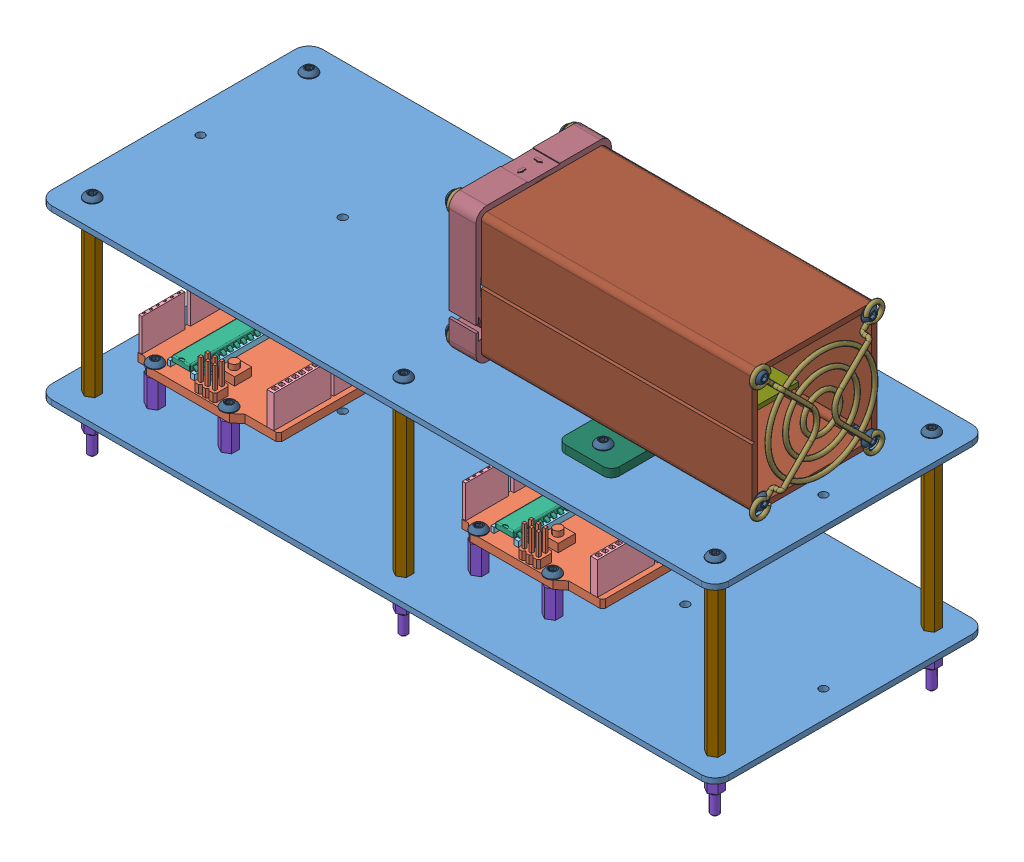
SolidWorks assembly control unit all, configuration Default. Lengths in mm.
Overall size (250 135.43 100).
72 component instances, 16 part files, 86 mates.
Components (placement in the parent):
- control unit enclosure buttom-1: control unit enclosure buttom [Default] at origin size (250 2 100)
- Arduino Uno-1: Arduino Uno [Predeterminado] at (82.475 -17.4682 -25.4621) x (0 0 1) z (-1 0 0) size (76.16 15 51.98)
  - Arduino Board-1: Arduino Board [Predeterminado] at (-14.2075 29.4682 76.4447) size (67.88 14 51.98)
  - Jam Socket-1: Jam Socket [Predeterminado] at origin size (12.01 7 9.62)
  - Pins Socket-1: Pins Socket [Predeterminado] at origin size (43.28 12 50.07)
  - Socket IC-1: Socket IC [Predeterminado] at origin size (35.47 2 10.08)
  - IC-1: IC [Predeterminado] at (0 34.4682 0) x (1 0 0) z (0 1 0) size (35.12 9.79 3)
  - Port USB-1: Port USB [Predeterminado] at (-14.2075 31.4682 76.4447) x (1 0 0) z (0 1 0) size (17.2 12.69 11)
- Arduino Uno-2: Arduino Uno [Predeterminado] at (-30.5497 -17.4682 -18.9941) x (0 0 1) z (-1 0 0) size (76.16 15 51.98)
  - Arduino Board-1: Arduino Board [Predeterminado] at (-14.2075 29.4682 76.4447) size (67.88 14 51.98)
  - Jam Socket-1: Jam Socket [Predeterminado] at origin size (12.01 7 9.62)
  - Pins Socket-1: Pins Socket [Predeterminado] at origin size (43.28 12 50.07)
  - Socket IC-1: Socket IC [Predeterminado] at origin size (35.47 2 10.08)
  - IC-1: IC [Predeterminado] at (0 34.4682 0) x (1 0 0) z (0 1 0) size (35.12 9.79 3)
  - Port USB-1: Port USB [Predeterminado] at (-14.2075 31.4682 76.4447) x (1 0 0) z (0 1 0) size (17.2 12.69 11)
- control unit enclosure buttom-2: control unit enclosure buttom [Default] at (0 62 0) size (250 2 100)
- Threaded spacer,mild steel,M3x10mm,MF-1: Threaded spacer,mild steel,M3x10mm,MF [Default] at (-115.0439 0 40.018) x (1 0 0) z (0 -1 0) size (5 5.77 18)
- Threaded spacer,mild steel,M3x10mm,MF-2: Threaded spacer,mild steel,M3x10mm,MF [Default] at (-0.0439 0 40.018) x (1 0 0) z (0 -1 0) size (5 5.77 18)
- Threaded spacer,mild steel,M3x10mm,MF-3: Threaded spacer,mild steel,M3x10mm,MF [Default] at (-0.0439 0 0.018) x (1 0 0) z (0 -1 0) size (5 5.77 18)
- Threaded spacer,mild steel,M3x10mm,MF-4: Threaded spacer,mild steel,M3x10mm,MF [Default] at (114.9561 0 40.018) x (1 0 0) z (0 -1 0) size (5 5.77 18)
- Threaded spacer,mild steel,M3x10mm,MF-5: Threaded spacer,mild steel,M3x10mm,MF [Default] at (114.9561 0 -39.982) x (1 0 0) z (0 -1 0) size (5 5.77 18)
- Threaded spacer,mild steel,M3x10mm,MF-6: Threaded spacer,mild steel,M3x10mm,MF [Default] at (-0.0439 0 -39.982) x (1 0 0) z (0 -1 0) size (5 5.77 18)
- Threaded spacer,mild steel,M3x10mm,MF-7: Threaded spacer,mild steel,M3x10mm,MF [Default] at (-115.0439 0 -39.982) x (1 0 0) z (0 -1 0) size (5 5.77 18)
- Threaded spacer,mild steel,M3x10mm,MF-8: Threaded spacer,mild steel,M3x10mm,MF [Default] at (8.6552 12 -25.8057) x (1 0 0) z (0 -1 0) size (5 5.77 18)
- Threaded spacer,mild steel,M3x10mm,MF-9: Threaded spacer,mild steel,M3x10mm,MF [Default] at (56.3988 12 -24.9534) x (1 0 0) z (0 -1 0) size (5 5.77 18)
- Threaded spacer,mild steel,M3x10mm,MF-10: Threaded spacer,mild steel,M3x10mm,MF [Default] at (41.1542 12 26.2142) x (1 0 0) z (0 -1 0) size (5 5.77 18)
- Threaded spacer,mild steel,M3x10mm,MF-11: Threaded spacer,mild steel,M3x10mm,MF [Default] at (13.5549 12 25.926) x (1 0 0) z (0 -1 0) size (5 5.77 18)
- Threaded spacer,mild steel,M3x10mm,MF-12: Threaded spacer,mild steel,M3x10mm,MF [Default] at (-56.6259 12 -18.4855) x (1 0 0) z (0 -1 0) size (5 5.77 18)
- Threaded spacer,mild steel,M3x10mm,MF-13: Threaded spacer,mild steel,M3x10mm,MF [Default] at (-71.8705 12 32.6822) x (1 0 0) z (0 -1 0) size (5 5.77 18)
- Threaded spacer,mild steel,M3x10mm,MF-14: Threaded spacer,mild steel,M3x10mm,MF [Default] at (-104.3696 12 -19.3378) x (1 0 0) z (0 -1 0) size (5 5.77 18)
- Threaded spacer,mild steel,M3x10mm,MF-15: Threaded spacer,mild steel,M3x10mm,MF [Default] at (-99.4698 12 32.394) x (1 0 0) z (0 -1 0) size (5 5.77 18)
- M3 60 Hex-1: M3 60 Hex [Default] at (-115.0439 62 -39.982) x (1 0 0) z (0 -1 0) size (5 5.77 60)
- M3 60 Hex-2: M3 60 Hex [Default] at (-0.0439 62 -39.982) x (1 0 0) z (0 -1 0) size (5 5.77 60)
- M3 60 Hex-3: M3 60 Hex [Default] at (114.9561 62 -39.982) x (1 0 0) z (0 -1 0) size (5 5.77 60)
- M3 60 Hex-4: M3 60 Hex [Default] at (114.9561 62 40.018) x (1 0 0) z (0 -1 0) size (5 5.77 60)
- M3 60 Hex-5: M3 60 Hex [Default] at (-0.0439 62 40.018) x (1 0 0) z (0 -1 0) size (5 5.77 60)
- M3 60 Hex-6: M3 60 Hex [Default] at (-115.0439 62 40.018) x (1 0 0) z (0 -1 0) size (5 5.77 60)
- Button Head Socket Cap Screw M3-3: Button Head Socket Cap Screw M3 [M3 x 6] at (56.4427 9 -24.9715) x (0 -1 0) z (0 0 1) size (7.72 5.7 5.7)
- Button Head Socket Cap Screw M3-4: Button Head Socket Cap Screw M3 [M3 x 6] at (41.1981 9 26.1962) x (0 -1 0) z (0 0 1) size (7.72 5.7 5.7)
- Button Head Socket Cap Screw M3-5: Button Head Socket Cap Screw M3 [M3 x 6] at (13.5988 9 25.908) x (0 -1 0) z (0 0 1) size (7.72 5.7 5.7)
- Button Head Socket Cap Screw M3-6: Button Head Socket Cap Screw M3 [M3 x 6] at (8.6991 9 -25.8238) x (0 -1 0) z (0 0 1) size (7.72 5.7 5.7)
- Button Head Socket Cap Screw M3-7: Button Head Socket Cap Screw M3 [M3 x 6] at (-99.4259 9 32.376) x (0 -1 0) z (0 0 1) size (7.72 5.7 5.7)
- Button Head Socket Cap Screw M3-8: Button Head Socket Cap Screw M3 [M3 x 6] at (-71.8267 9 32.6642) x (0 -1 0) z (0 0 1) size (7.72 5.7 5.7)
- Button Head Socket Cap Screw M3-9: Button Head Socket Cap Screw M3 [M3 x 6] at (-56.582 9 -18.5035) x (0 -1 0) z (0 0 1) size (7.72 5.7 5.7)
- Button Head Socket Cap Screw M3-10: Button Head Socket Cap Screw M3 [M3 x 6] at (-104.3257 9 -19.3558) x (0 -1 0) z (0 0 1) size (7.72 5.7 5.7)
- laser driver all-1: laser driver all [Default] at (137.2946 173.2943 62.6746) x (0 0 -1) z (-1 0 0) size (70 56.43 120.4)
  - laser driver box main body-1: laser driver box main body [Default] at (63.0779 83.2943 26.0047) x (1 0 0) z (0 -1 0) size (46 100 46)
  - 50mm fan grill-1: 50mm fan grill [Default] at (63.0022 83.1988 136.0042) x (1 0 0) z (0 -1 0) size (49.4 5.46 49.4)
  - Button Head Socket Cap Screw M3-1: Button Head Socket Cap Screw M3 [M3 x 12] at (84.0779 62.2943 126.0047) x (0 0 -1) z (1 0 0) size (13.72 5.7 5.7)
  - Button Head Socket Cap Screw M3-2: Button Head Socket Cap Screw M3 [M3 x 12] at (42.0779 62.2943 126.0047) x (0 0 -1) z (1 0 0) size (13.72 5.7 5.7)
  - Button Head Socket Cap Screw M3-3: Button Head Socket Cap Screw M3 [M3 x 12] at (42.0779 104.2943 126.0047) x (0 0 -1) z (1 0 0) size (13.72 5.7 5.7)
  - Button Head Socket Cap Screw M3-4: Button Head Socket Cap Screw M3 [M3 x 12] at (84.0779 104.2943 126.0047) x (0 0 -1) z (1 0 0) size (13.72 5.7 5.7)
  - fan_asm-2: fan_asm [Default] at (-332.7982 222.9958 136.0047) x (1 0 0) z (0 1 0) size (54.48 10.28 54.48)
    - fan_case-1: fan_case [Default] at origin size (50 10.1 50)
    - fan-1: fan [Default] at (415.4421 3.5826 -113.9746) x (0.605351 0 0.795959) z (0.795959 0 -0.605351) size (45.4 7.28 44.65)
  - laser driver box mouinting-1: laser driver box mouinting [Default] at (63.0779 106.2943 76.0047) size (70 3 20)
  - Threaded spacer,mild steel,M3x10mm,MF-1: Threaded spacer,mild steel,M3x10mm,MF [Default] at (55.0779 94.2943 76.0047) x (0.924886 0 -0.380244) z (0 1 0) size (5 5.77 18)
  - Threaded spacer,mild steel,M3x10mm,MF-2: Threaded spacer,mild steel,M3x10mm,MF [Default] at (71.0779 94.2943 76.0047) x (0.924886 0 -0.380244) z (0 1 0) size (5 5.77 18)
  - laser driver-1: laser driver [Default] at (61.0703 92.6943 71.0647) x (0 0 1) z (-1 0 0) size (49.14 1.6 33.19)
  - 50mm fan grill-3: 50mm fan grill [Default] at (63.1151 83.7042 25.8617) x (1 0 0) z (0 1 0) size (49.4 5.46 49.4)
  - Button Head Socket Cap Screw M3-5: Button Head Socket Cap Screw M3 [M3 x 6] at (43.0779 63.2943 32.0047) x (0 0 1) z (-1 0 0) size (7.72 5.7 5.7)
  - Button Head Socket Cap Screw M3-6: Button Head Socket Cap Screw M3 [M3 x 6] at (43.0779 103.2943 32.0047) x (0 0 1) z (-0.67555 -0.737314 0) size (7.72 5.7 5.7)
  - Button Head Socket Cap Screw M3-7: Button Head Socket Cap Screw M3 [M3 x 6] at (83.0779 103.2943 32.0047) x (0 0 1) z (-1 0 0) size (7.72 5.7 5.7)
  - Button Head Socket Cap Screw M3-8: Button Head Socket Cap Screw M3 [M3 x 6] at (83.0779 63.2943 32.0047) x (0 0 1) z (-1 0 0) size (7.72 5.7 5.7)
- Button Head Socket Cap Screw M3-11: Button Head Socket Cap Screw M3 [M3 x 6] at (115 58 -40) x (0 -1 0) z (0 0 1) size (7.72 5.7 5.7)
- Button Head Socket Cap Screw M3-12: Button Head Socket Cap Screw M3 [M3 x 6] at (115 58 40) x (0 -1 0) z (0 0 1) size (7.72 5.7 5.7)
- Button Head Socket Cap Screw M3-13: Button Head Socket Cap Screw M3 [M3 x 6] at (0 58 -40) x (0 -1 0) z (0 0 1) size (7.72 5.7 5.7)
- Button Head Socket Cap Screw M3-14: Button Head Socket Cap Screw M3 [M3 x 6] at (-115 58 -40) x (0 -1 0) z (0 0 1) size (7.72 5.7 5.7)
- Button Head Socket Cap Screw M3-15: Button Head Socket Cap Screw M3 [M3 x 6] at (-115 58 40) x (0 -1 0) z (0 0 1) size (7.72 5.7 5.7)
- Button Head Socket Cap Screw M3-16: Button Head Socket Cap Screw M3 [M3 x 6] at (0 58 40) x (0 -1 0) z (0 0 1) size (7.72 5.7 5.7)
- Button Head Socket Cap Screw M3-17: Button Head Socket Cap Screw M3 [M3 x 10] at (61.2899 57 -28.4033) x (0 -1 0) z (0 0 1) size (11.72 5.7 5.7)
- Button Head Socket Cap Screw M3-18: Button Head Socket Cap Screw M3 [M3 x 10] at (61.2899 57 27.5967) x (0 -1 0) z (0 0 1) size (11.72 5.7 5.7)
Mates (geometry in assembly coordinates):
- Coincident1: coincident anti-aligned: plane of control unit enclosure buttom-1 through (120 0 -45) normal (0 -1 0); plane of Threaded spacer,mild steel,M3x10mm,MF-7 through (-117.5439 0 -42.9034) normal (0 1 0)
- Coincident2: coincident anti-aligned: plane of control unit enclosure buttom-1 through (120 0 -45) normal (0 -1 0); plane of Threaded spacer,mild steel,M3x10mm,MF-1 through (-117.5439 0 37.0966) normal (0 1 0)
- Coincident3: coincident anti-aligned: plane of control unit enclosure buttom-1 through (120 0 -45) normal (0 -1 0); plane of Threaded spacer,mild steel,M3x10mm,MF-2 through (-2.5439 0 37.0966) normal (0 1 0)
- Coincident4: coincident anti-aligned: plane of control unit enclosure buttom-1 through (120 0 -45) normal (0 -1 0); plane of Threaded spacer,mild steel,M3x10mm,MF-3 through (-2.5439 0 -2.9034) normal (0 1 0)
- Coincident5: coincident anti-aligned: plane of control unit enclosure buttom-1 through (120 0 -45) normal (0 -1 0); plane of Threaded spacer,mild steel,M3x10mm,MF-6 through (-2.5439 0 -42.9034) normal (0 1 0)
- Coincident6: coincident anti-aligned: plane of control unit enclosure buttom-1 through (120 0 -45) normal (0 -1 0); plane of Threaded spacer,mild steel,M3x10mm,MF-4 through (112.4561 0 37.0966) normal (0 1 0)
- Coincident7: coincident anti-aligned: plane of control unit enclosure buttom-1 through (120 0 -45) normal (0 -1 0); plane of Threaded spacer,mild steel,M3x10mm,MF-5 through (112.4561 0 -42.9034) normal (0 1 0)
- Concentric1: concentric aligned: cylinder of control unit enclosure buttom-1 through (-115 2 -40) axis (0 -1 0) radius 1.5; cylinder of Threaded spacer,mild steel,M3x10mm,MF-7 through (-115 -8.5 -40) axis (0 -1 0) radius 1.5
- Concentric3: concentric aligned: cylinder of control unit enclosure buttom-1 through (-115 2 40) axis (0 -1 0) radius 1.5; cylinder of Threaded spacer,mild steel,M3x10mm,MF-1 through (-115 -8.5 40) axis (0 -1 0) radius 1.5
- Concentric4: concentric aligned: cylinder of control unit enclosure buttom-1 through (0 2 40) axis (0 -1 0) radius 1.5; cylinder of Threaded spacer,mild steel,M3x10mm,MF-2 through (0 -8.5 40) axis (0 -1 0) radius 1.5
- Concentric5: concentric aligned: cylinder of control unit enclosure buttom-1 through (0 2 -40) axis (0 -1 0) radius 1.5; cylinder of Threaded spacer,mild steel,M3x10mm,MF-6 through (0 -8.5 -40) axis (0 -1 0) radius 1.5
- Concentric6: concentric aligned: cylinder of control unit enclosure buttom-1 through (0 2 0) axis (0 -1 0) radius 1.5; cylinder of Threaded spacer,mild steel,M3x10mm,MF-3 through (0 -8.5 0) axis (0 -1 0) radius 1.5
- Concentric7: concentric aligned: cylinder of control unit enclosure buttom-1 through (115 2 40) axis (0 -1 0) radius 1.5; cylinder of Threaded spacer,mild steel,M3x10mm,MF-4 through (115 -8.5 40) axis (0 -1 0) radius 1.5
- Concentric8: concentric aligned: cylinder of control unit enclosure buttom-1 through (115 2 -40) axis (0 -1 0) radius 1.5; cylinder of Threaded spacer,mild steel,M3x10mm,MF-5 through (115 -8.5 -40) axis (0 -1 0) radius 1.5
- Concentric9: concentric anti-aligned: cylinder of Arduino Uno-1/Arduino Board-1 through (8.6991 10 -25.8238) axis (0 1 0) radius 1.5591; cylinder of Threaded spacer,mild steel,M3x10mm,MF-8 through (8.6991 3.5 -25.8238) axis (0 -1 0) radius 1.5
- Coincident8: coincident anti-aligned: plane of Arduino Uno-1/Arduino Board-1 through (6.0303 12 -39.6695) normal (0 -1 0); plane of Threaded spacer,mild steel,M3x10mm,MF-8 through (6.1552 12 -28.7271) normal (0 1 0)
- Coincident9: coincident anti-aligned: plane of Arduino Uno-1/Arduino Board-1 through (6.0303 12 -39.6695) normal (0 -1 0); plane of Threaded spacer,mild steel,M3x10mm,MF-9 through (53.8988 12 -27.8748) normal (0 1 0)
- Coincident10: coincident anti-aligned: plane of Arduino Uno-1/Arduino Board-1 through (6.0303 12 -39.6695) normal (0 -1 0); plane of Threaded spacer,mild steel,M3x10mm,MF-10 through (38.6542 12 23.2929) normal (0 1 0)
- Coincident11: coincident anti-aligned: plane of Arduino Uno-1/Arduino Board-1 through (6.0303 12 -39.6695) normal (0 -1 0); plane of Threaded spacer,mild steel,M3x10mm,MF-11 through (11.0549 12 23.0046) normal (0 1 0)
- Concentric10: concentric anti-aligned: cylinder of Threaded spacer,mild steel,M3x10mm,MF-9 through (56.4427 3.5 -24.9715) axis (0 -1 0) radius 1.5; cylinder of Arduino Uno-1/Arduino Board-1 through (56.4427 10 -24.9715) axis (0 1 0) radius 1.7436
- Concentric11: concentric anti-aligned: cylinder of Arduino Uno-1/Arduino Board-1 through (41.1981 10 26.1962) axis (0 1 0) radius 1.5708; cylinder of Threaded spacer,mild steel,M3x10mm,MF-10 through (41.1981 3.5 26.1962) axis (0 -1 0) radius 1.5
- Concentric12: concentric anti-aligned: cylinder of Arduino Uno-1/Arduino Board-1 through (13.5988 10 25.908) axis (0 1 0) radius 1.5451; cylinder of Threaded spacer,mild steel,M3x10mm,MF-11 through (13.5988 3.5 25.908) axis (0 -1 0) radius 1.5
- Coincident12: coincident anti-aligned: plane of Arduino Uno-2/Arduino Board-1 through (-106.9944 12 -33.2016) normal (0 -1 0); plane of Threaded spacer,mild steel,M3x10mm,MF-15 through (-101.9698 12 29.4726) normal (0 1 0)
- Coincident13: coincident anti-aligned: plane of Arduino Uno-2/Arduino Board-1 through (-106.9944 12 -33.2016) normal (0 -1 0); plane of Threaded spacer,mild steel,M3x10mm,MF-13 through (-74.3705 12 29.7608) normal (0 1 0)
- Coincident14: coincident anti-aligned: plane of Arduino Uno-2/Arduino Board-1 through (-106.9944 12 -33.2016) normal (0 -1 0); plane of Threaded spacer,mild steel,M3x10mm,MF-12 through (-59.1259 12 -21.4069) normal (0 1 0)
- Coincident15: coincident anti-aligned: plane of Arduino Uno-2/Arduino Board-1 through (-106.9944 12 -33.2016) normal (0 -1 0); plane of Threaded spacer,mild steel,M3x10mm,MF-14 through (-106.8696 12 -22.2592) normal (0 1 0)
- Concentric13: concentric anti-aligned: cylinder of Arduino Uno-2/Arduino Board-1 through (-99.4259 10 32.376) axis (0 1 0) radius 1.5451; cylinder of Threaded spacer,mild steel,M3x10mm,MF-15 through (-99.4259 3.5 32.376) axis (0 -1 0) radius 1.5
- Concentric14: concentric anti-aligned: cylinder of Arduino Uno-2/Arduino Board-1 through (-104.3257 10 -19.3558) axis (0 1 0) radius 1.5591; cylinder of Threaded spacer,mild steel,M3x10mm,MF-14 through (-104.3257 3.5 -19.3558) axis (0 -1 0) radius 1.5
- Concentric15: concentric anti-aligned: cylinder of Arduino Uno-2/Arduino Board-1 through (-56.582 10 -18.5035) axis (0 1 0) radius 1.7436; cylinder of Threaded spacer,mild steel,M3x10mm,MF-12 through (-56.582 3.5 -18.5035) axis (0 -1 0) radius 1.5
- Concentric16: concentric anti-aligned: cylinder of Arduino Uno-2/Arduino Board-1 through (-71.8267 10 32.6642) axis (0 1 0) radius 1.5708; cylinder of Threaded spacer,mild steel,M3x10mm,MF-13 through (-71.8267 3.5 32.6642) axis (0 -1 0) radius 1.5
- Coincident16: coincident anti-aligned: plane of control unit enclosure buttom-1 through (120 2 -45) normal (0 1 0); plane of Threaded spacer,mild steel,M3x10mm,MF-12 through (-55.3834 2 -20.6635) normal (0 -1 0)
- Parallel1: parallel anti-aligned: plane of control unit enclosure buttom-1 through (120 2 -45) normal (0 1 0); plane of Threaded spacer,mild steel,M3x10mm,MF-9 through (55.1338 2 -27.8445) normal (0 -1 0)
- Coincident20: coincident anti-aligned: plane of control unit enclosure buttom-1 through (120 2 -45) normal (0 1 0); plane of Threaded spacer,mild steel,M3x10mm,MF-9 through (55.1338 2 -27.8445) normal (0 -1 0)
- Coincident22: coincident anti-aligned: plane of control unit enclosure buttom-1 through (120 2 -45) normal (0 1 0); plane of M3 60 Hex-2 through (-2.5439 2 -35.6518) normal (0 -1 0)
- Coincident23: coincident anti-aligned: plane of control unit enclosure buttom-1 through (120 2 -45) normal (0 1 0); plane of M3 60 Hex-3 through (112.4561 2 -35.6518) normal (0 -1 0)
- Coincident24: coincident anti-aligned: plane of control unit enclosure buttom-1 through (120 2 -45) normal (0 1 0); plane of M3 60 Hex-4 through (112.4561 2 44.3482) normal (0 -1 0)
- Coincident25: coincident anti-aligned: plane of control unit enclosure buttom-1 through (120 2 -45) normal (0 1 0); plane of M3 60 Hex-5 through (-2.5439 2 44.3482) normal (0 -1 0)
- Coincident26: coincident anti-aligned: plane of control unit enclosure buttom-1 through (120 2 -45) normal (0 1 0); plane of M3 60 Hex-6 through (-117.5439 2 44.3482) normal (0 -1 0)
- Coincident27: coincident anti-aligned: plane of control unit enclosure buttom-1 through (120 2 -45) normal (0 1 0); plane of M3 60 Hex-1 through (-117.5439 2 -35.6518) normal (0 -1 0)
- Concentric17: concentric anti-aligned: cylinder of control unit enclosure buttom-1 through (115 2 40) axis (0 -1 0) radius 1.5; cylinder of M3 60 Hex-4 through (115 2 40) axis (0 1 0) radius 1.25
- Concentric18: concentric anti-aligned: cylinder of control unit enclosure buttom-1 through (115 2 -40) axis (0 -1 0) radius 1.5; cylinder of M3 60 Hex-3 through (115 2 -40) axis (0 1 0) radius 1.25
- Concentric19: concentric anti-aligned: cylinder of control unit enclosure buttom-1 through (0 2 -40) axis (0 -1 0) radius 1.5; cylinder of M3 60 Hex-2 through (0 2 -40) axis (0 1 0) radius 1.25
- Concentric20: concentric anti-aligned: cylinder of control unit enclosure buttom-1 through (-115 2 -40) axis (0 -1 0) radius 1.5; cylinder of M3 60 Hex-1 through (-115 2 -40) axis (0 1 0) radius 1.25
- Concentric21: concentric anti-aligned: cylinder of control unit enclosure buttom-1 through (-115 2 40) axis (0 -1 0) radius 1.5; cylinder of M3 60 Hex-6 through (-115 2 40) axis (0 1 0) radius 1.25
- Concentric22: concentric anti-aligned: cylinder of control unit enclosure buttom-1 through (0 2 40) axis (0 -1 0) radius 1.5; cylinder of M3 60 Hex-5 through (0 2 40) axis (0 1 0) radius 1.25
- Concentric271: concentric anti-aligned: cylinder of Arduino Uno-1/Arduino Board-1 through (56.4427 10 -24.9715) axis (0 1 0) radius 1.7436; cylinder of Button Head Socket Cap Screw M3-3 through (56.4427 15 -24.9715) axis (0 -1 0) radius 2.85
- Coincident321: coincident anti-aligned: plane of Arduino Uno-1/Arduino Board-1 through (6.0303 15 -39.6695) normal (0 1 0); plane of Button Head Socket Cap Screw M3-3 through (59.2927 15 -24.9715) normal (0 -1 0)
- Concentric281: concentric anti-aligned: cylinder of Arduino Uno-1/Arduino Board-1 through (41.1981 10 26.1962) axis (0 1 0) radius 1.5708; cylinder of Button Head Socket Cap Screw M3-4 through (41.1981 15 26.1962) axis (0 -1 0) radius 2.85
- Coincident331: coincident anti-aligned: plane of Arduino Uno-1/Arduino Board-1 through (6.0303 15 -39.6695) normal (0 1 0); plane of Button Head Socket Cap Screw M3-4 through (44.0481 15 26.1962) normal (0 -1 0)
- Concentric291: concentric anti-aligned: cylinder of Arduino Uno-1/Arduino Board-1 through (13.5988 10 25.908) axis (0 1 0) radius 1.5451; cylinder of Button Head Socket Cap Screw M3-5 through (13.5988 15 25.908) axis (0 -1 0) radius 2.85
- Coincident341: coincident anti-aligned: plane of Arduino Uno-1/Arduino Board-1 through (6.0303 15 -39.6695) normal (0 1 0); plane of Button Head Socket Cap Screw M3-5 through (16.4488 15 25.908) normal (0 -1 0)
- Concentric301: concentric anti-aligned: cylinder of Arduino Uno-1/Arduino Board-1 through (8.6991 10 -25.8238) axis (0 1 0) radius 1.5591; cylinder of Button Head Socket Cap Screw M3-6 through (8.6991 15 -25.8238) axis (0 -1 0) radius 2.85
- Coincident351: coincident anti-aligned: plane of Arduino Uno-1/Arduino Board-1 through (6.0303 15 -39.6695) normal (0 1 0); plane of Button Head Socket Cap Screw M3-6 through (11.5491 15 -25.8238) normal (0 -1 0)
- Concentric311: concentric anti-aligned: cylinder of Arduino Uno-2/Arduino Board-1 through (-99.4259 10 32.376) axis (0 1 0) radius 1.5451; cylinder of Button Head Socket Cap Screw M3-7 through (-99.4259 15 32.376) axis (0 -1 0) radius 2.85
- Coincident361: coincident anti-aligned: plane of Arduino Uno-2/Arduino Board-1 through (-106.9944 15 -33.2016) normal (0 1 0); plane of Button Head Socket Cap Screw M3-7 through (-96.5759 15 32.376) normal (0 -1 0)
- Concentric321: concentric anti-aligned: cylinder of Arduino Uno-2/Arduino Board-1 through (-71.8267 10 32.6642) axis (0 1 0) radius 1.5708; cylinder of Button Head Socket Cap Screw M3-8 through (-71.8267 15 32.6642) axis (0 -1 0) radius 2.85
- Coincident371: coincident anti-aligned: plane of Arduino Uno-2/Arduino Board-1 through (-106.9944 15 -33.2016) normal (0 1 0); plane of Button Head Socket Cap Screw M3-8 through (-68.9767 15 32.6642) normal (0 -1 0)
- Concentric331: concentric anti-aligned: cylinder of Arduino Uno-2/Arduino Board-1 through (-56.582 10 -18.5035) axis (0 1 0) radius 1.7436; cylinder of Button Head Socket Cap Screw M3-9 through (-56.582 15 -18.5035) axis (0 -1 0) radius 2.85
- Coincident381: coincident anti-aligned: plane of Arduino Uno-2/Arduino Board-1 through (-106.9944 15 -33.2016) normal (0 1 0); plane of Button Head Socket Cap Screw M3-9 through (-53.732 15 -18.5035) normal (0 -1 0)
- Concentric341: concentric anti-aligned: cylinder of Arduino Uno-2/Arduino Board-1 through (-104.3257 10 -19.3558) axis (0 1 0) radius 1.5591; cylinder of Button Head Socket Cap Screw M3-10 through (-104.3257 15 -19.3558) axis (0 -1 0) radius 2.85
- Coincident391: coincident anti-aligned: plane of Arduino Uno-2/Arduino Board-1 through (-106.9944 15 -33.2016) normal (0 1 0); plane of Button Head Socket Cap Screw M3-10 through (-101.4757 15 -19.3558) normal (0 -1 0)
- Coincident41: coincident anti-aligned: plane of control unit enclosure buttom-2 through (120 62 -45) normal (0 -1 0); plane of M3 60 Hex-3 through (112.4561 62 -35.6518) normal (0 1 0)
- Coincident42: coincident anti-aligned: plane of control unit enclosure buttom-2 through (120 62 -45) normal (0 -1 0); plane of M3 60 Hex-6 through (-117.5439 62 44.3482) normal (0 1 0)
- Concentric35: concentric aligned: cylinder of control unit enclosure buttom-2 through (-115 64 -40) axis (0 -1 0) radius 1.5; cylinder of M3 60 Hex-1 through (-115 62 -40) axis (0 -1 0) radius 1.25
- Concentric36: concentric aligned: cylinder of control unit enclosure buttom-2 through (-115 64 40) axis (0 -1 0) radius 1.5; cylinder of M3 60 Hex-6 through (-115 62 40) axis (0 -1 0) radius 1.25
- Concentric37: concentric aligned: cylinder of control unit enclosure buttom-2 through (0 64 -40) axis (0 -1 0) radius 1.5; cylinder of M3 60 Hex-2 through (0 62 -40) axis (0 -1 0) radius 1.25
- Concentric39: concentric aligned: cylinder of control unit enclosure buttom-2 through (0 64 40) axis (0 -1 0) radius 1.5; cylinder of M3 60 Hex-5 through (0 62 40) axis (0 -1 0) radius 1.25
- Concentric40: concentric aligned: cylinder of control unit enclosure buttom-2 through (115 64 40) axis (0 -1 0) radius 1.5; cylinder of M3 60 Hex-4 through (115 62 40) axis (0 -1 0) radius 1.25
- Concentric41: concentric aligned: cylinder of control unit enclosure buttom-2 through (115 64 -40) axis (0 -1 0) radius 1.5; cylinder of M3 60 Hex-3 through (115 62 -40) axis (0 -1 0) radius 1.25
- Coincident392: coincident anti-aligned: plane of control unit enclosure buttom-2 through (120 64 -45) normal (0 1 0); plane of laser driver all-1/laser driver box mouinting-1 through (68.2899 64 -32.4033) normal (0 -1 0)
- Concentric3421: concentric aligned: cylinder of control unit enclosure buttom-2 through (115 64 -40) axis (0 -1 0) radius 1.5; cylinder of Button Head Socket Cap Screw M3-11 through (115 64 -40) axis (0 -1 0) radius 2.85
- Coincident3931: coincident anti-aligned: plane of control unit enclosure buttom-2 through (120 64 -45) normal (0 1 0); plane of Button Head Socket Cap Screw M3-11 through (117.85 64 -40) normal (0 -1 0)
- Concentric3431: concentric aligned: cylinder of control unit enclosure buttom-2 through (115 64 40) axis (0 -1 0) radius 1.5; cylinder of Button Head Socket Cap Screw M3-12 through (115 64 40) axis (0 -1 0) radius 2.85
- Coincident3941: coincident anti-aligned: plane of control unit enclosure buttom-2 through (120 64 -45) normal (0 1 0); plane of Button Head Socket Cap Screw M3-12 through (117.85 64 40) normal (0 -1 0)
- Concentric3441: concentric aligned: cylinder of control unit enclosure buttom-2 through (0 64 -40) axis (0 -1 0) radius 1.5; cylinder of Button Head Socket Cap Screw M3-13 through (0 64 -40) axis (0 -1 0) radius 2.85
- Coincident3951: coincident anti-aligned: plane of control unit enclosure buttom-2 through (120 64 -45) normal (0 1 0); plane of Button Head Socket Cap Screw M3-13 through (2.85 64 -40) normal (0 -1 0)
- Concentric3451: concentric aligned: cylinder of control unit enclosure buttom-2 through (-115 64 -40) axis (0 -1 0) radius 1.5; cylinder of Button Head Socket Cap Screw M3-14 through (-115 64 -40) axis (0 -1 0) radius 2.85
- Coincident3961: coincident anti-aligned: plane of control unit enclosure buttom-2 through (120 64 -45) normal (0 1 0); plane of Button Head Socket Cap Screw M3-14 through (-112.15 64 -40) normal (0 -1 0)
- Concentric3461: concentric aligned: cylinder of control unit enclosure buttom-2 through (-115 64 40) axis (0 -1 0) radius 1.5; cylinder of Button Head Socket Cap Screw M3-15 through (-115 64 40) axis (0 -1 0) radius 2.85
- Coincident3971: coincident anti-aligned: plane of control unit enclosure buttom-2 through (120 64 -45) normal (0 1 0); plane of Button Head Socket Cap Screw M3-15 through (-112.15 64 40) normal (0 -1 0)
- Concentric3471: concentric aligned: cylinder of control unit enclosure buttom-2 through (0 64 40) axis (0 -1 0) radius 1.5; cylinder of Button Head Socket Cap Screw M3-16 through (0 64 40) axis (0 -1 0) radius 2.85
- Coincident3981: coincident anti-aligned: plane of control unit enclosure buttom-2 through (120 64 -45) normal (0 1 0); plane of Button Head Socket Cap Screw M3-16 through (2.85 64 40) normal (0 -1 0)
- Concentric3481: concentric anti-aligned: cylinder of laser driver all-1/laser driver box mouinting-1 through (61.2899 64 -28.4033) axis (0 1 0) radius 1.5; cylinder of Button Head Socket Cap Screw M3-17 through (61.2899 67 -28.4033) axis (0 -1 0) radius 2.85
- Coincident3991: coincident anti-aligned: plane of laser driver all-1/laser driver box mouinting-1 through (68.2899 67 -32.4033) normal (0 1 0); plane of Button Head Socket Cap Screw M3-17 through (64.1399 67 -28.4033) normal (0 -1 0)
- Concentric3491: concentric anti-aligned: cylinder of laser driver all-1/laser driver box mouinting-1 through (61.2899 64 27.5967) axis (0 1 0) radius 1.5; cylinder of Button Head Socket Cap Screw M3-18 through (61.2899 67 27.5967) axis (0 -1 0) radius 2.85
- Coincident4001: coincident anti-aligned: plane of laser driver all-1/laser driver box mouinting-1 through (68.2899 67 -32.4033) normal (0 1 0); plane of Button Head Socket Cap Screw M3-18 through (64.1399 67 27.5967) normal (0 -1 0)
